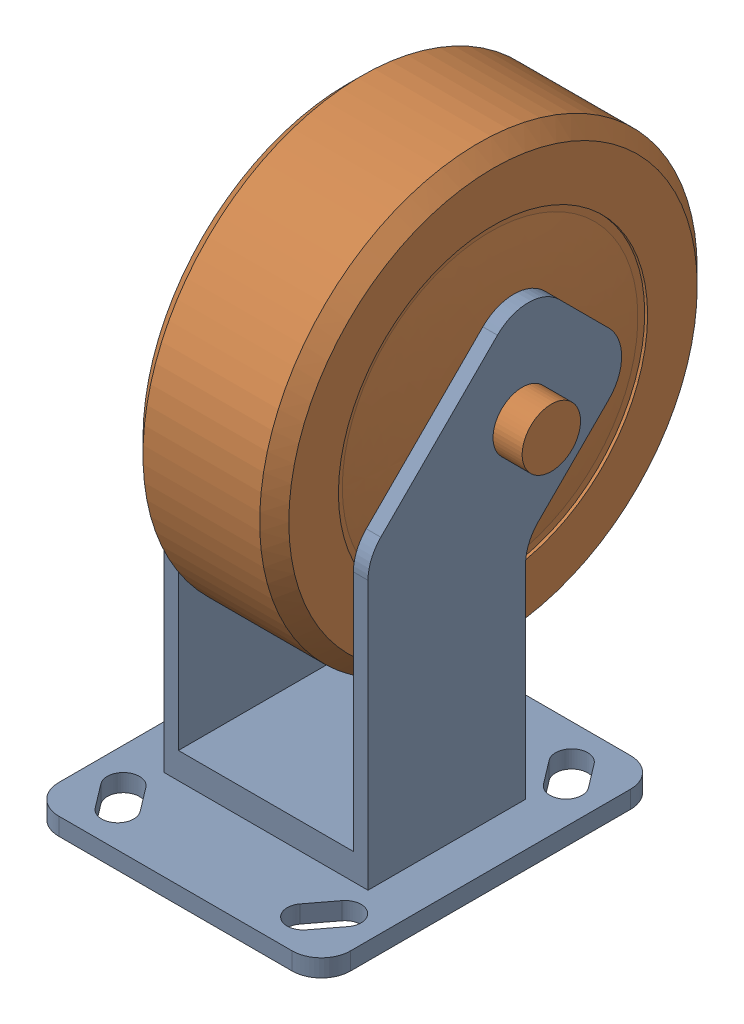
SolidWorks assembly Wheelasssembly, configuration Default. Lengths in mm.
Overall size (100 193.9 158.85).
2 component instances, 2 part files, 2 mates.
Components (placement in the parent):
- 1TrolleyWheelSupport-1: 1TrolleyWheelSupport [Default] at (37.9636 23.3598 114.9093) size (100 152.99 117.95)
- 1TrolleyWheel-1: 1TrolleyWheel [Default] at (37.9636 142.258 89.0548) size (90 150 150)
Mates (geometry in assembly coordinates):
- Concentric1: concentric: cylinder of 1TrolleyWheelSupport-1 through (67.9636 142.258 89.0548) axis (1 0 0) radius 8; cylinder of 1TrolleyWheel-1 through (72.9636 142.258 89.0548) axis (-1 0 0) radius 8
- Coincident1: coincident: plane of 1TrolleyWheelSupport-1 through (72.9636 38.3598 87.9093) normal (1 0 0); plane of 1TrolleyWheel-1 through (72.9636 142.258 89.0548) normal (-1 0 0)
